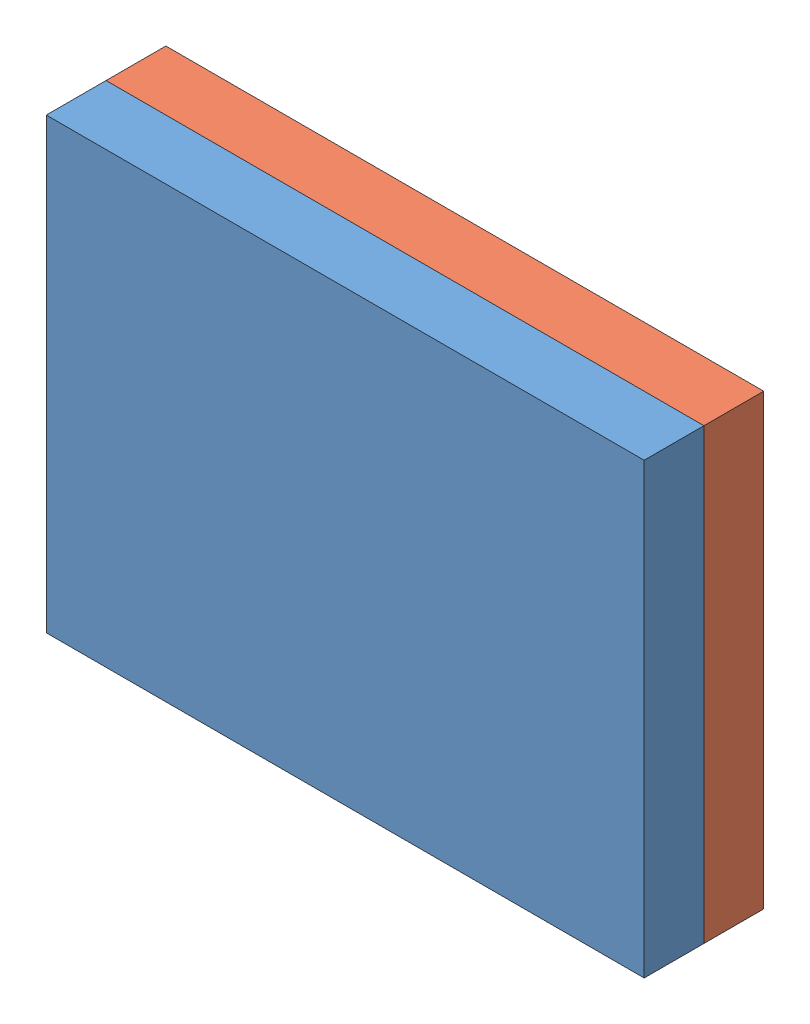
SolidWorks assembly Assem1, configuration Default. Lengths in mm.
Overall size (200 150 50).
2 component instances, 2 part files, 3 mates.
Components (placement in the parent):
- base 1-1: base 1 [Default] at (-34.7552 -110.3677 -159.0567) size (200 150 50)
- plate-2: plate [Default] at (-34.7552 -110.3677 -179.0567) size (200 150 20)
Mates (geometry in assembly coordinates):
- Coincident2: coincident anti-aligned: plane of base 1-1 through (-34.7552 -110.3677 -159.0567) normal (0 0 -1); plane of plate-2 through (-34.7552 -110.3677 -159.0567) normal (0 0 1)
- Concentric1: concentric anti-aligned: cylinder of base 1-1 through (-84.7552 -65.3677 -189.0567) axis (0 0 1) radius 15; cylinder of plate-2 through (-84.7552 -65.3677 -159.0567) axis (0 0 -1) radius 17
- Concentric5: concentric anti-aligned: cylinder of base 1-1 through (15.2448 -155.3677 -189.0567) axis (0 0 1) radius 10; cylinder of plate-2 through (15.2448 -155.3677 -159.0567) axis (0 0 -1) radius 11.25
